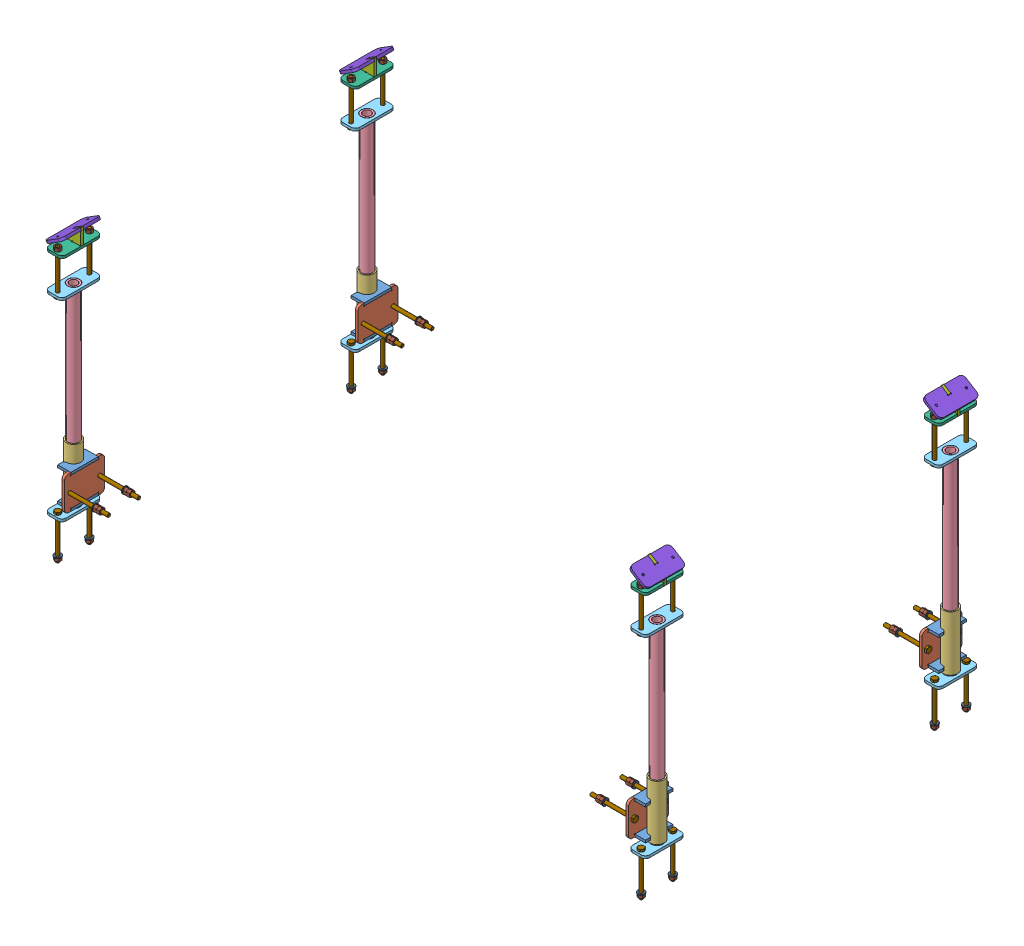
SolidWorks assembly Sliding mechanism^SPR-V1 0000.00-A Sheetpress assembly, configuration Default. Lengths in mm.
Overall size (1428.35 678.14 790).
108 component instances, 11 part files, 0 mates.
Components (placement in the parent):
- SPR-V1 1000.02-A Guide bracket-1: SPR-V1 1000.02-A Guide bracket [Default] at (665 -300 0) x (0 0 1) z (1 0 0) size (65 80 31)
- SPR-V1 1000.02-A Guide plate-1: SPR-V1 1000.02-A Guide plate [Default] at (665 -300 0) x (0 0 1) z (1 0 0) size (95 80 6)
- SPR-V1 1000.02-A Slider guide-1: SPR-V1 1000.02-A Slider guide [Default] at (665 -320 0) x (0 0 -1) z (0 1 0) size (34 34 130)
- SPR-V1 1000.03-A Slider rod-1: SPR-V1 1000.03-A Slider rod [Default] at (671 -420 0) x (0 0 -1) z (0 1 0) size (27 27 460)
- SPR-V1 1000.04-A Slider rod plate-1: SPR-V1 1000.04-A Slider rod plate [Default] at (671 -420 0) x (0 0 -1) z (0 1 0) size (95 40 6)
- SPR-V1 1000.05-A Hood bracket 1-1: SPR-V1 1000.05-A Hood bracket 1 [Default] at (0 120 0) x (1 0 0) z (0 1 0) size (40 95 6)
- SPR-V1 1000.05-A Hood bracket 2-1: SPR-V1 1000.05-A Hood bracket 2 [Default] at (0 0 -347.5) size (40 44.14 6)
- SPR-V1 1000.05-A Hood bracket 3-1: SPR-V1 1000.05-A Hood bracket 3 [Default] at (0 0 -347.5) size (44.82 31.06 95)
- SPR-V1 1000.02-A Slider guide-2: SPR-V1 1000.02-A Slider guide [Default] at (665 -370 0) x (0 0 1) z (0 -1 0) size (34 34 130)
- SPR-V1 1000.03-A Slider rod-2: SPR-V1 1000.03-A Slider rod [Default] at (671 40 0) x (0 0 1) z (0 -1 0) size (27 27 460)
- SPR-V1 1000.02-A Guide bracket-2: SPR-V1 1000.02-A Guide bracket [Default] at (665 -300 695) x (0 0 1) z (1 0 0) size (65 80 31)
- SPR-V1 1000.02-A Slider guide-3: SPR-V1 1000.02-A Slider guide [Default] at (-665 -370 0) x (0 0 -1) z (0 -1 0) size (34 34 130)
- SPR-V1 1000.03-A Slider rod-3: SPR-V1 1000.03-A Slider rod [Default] at (-671 40 0) x (0 0 -1) z (0 -1 0) size (27 27 460)
- SPR-V1 1000.02-A Guide bracket-3: SPR-V1 1000.02-A Guide bracket [Default] at (-665 -300 -695) x (0 0 -1) z (-1 0 0) size (65 80 31)
- SPR-V1 1000.02-A Slider guide-4: SPR-V1 1000.02-A Slider guide [Default] at (-665 -320 0) x (0 0 1) z (0 1 0) size (34 34 130)
- SPR-V1 1000.03-A Slider rod-4: SPR-V1 1000.03-A Slider rod [Default] at (-671 -420 0) x (0 0 1) z (0 1 0) size (27 27 460)
- SPR-V1 1000.02-A Guide bracket-4: SPR-V1 1000.02-A Guide bracket [Default] at (-665 -300 0) x (0 0 -1) z (-1 0 0) size (65 80 31)
- SPR-V1 1000.02-A Guide plate-2: SPR-V1 1000.02-A Guide plate [Default] at (671 -300 0) x (0 0 -1) z (-1 0 0) size (95 80 6)
- SPR-V1 1000.02-A Guide plate-3: SPR-V1 1000.02-A Guide plate [Default] at (-665 -300 0) x (0 0 -1) z (-1 0 0) size (95 80 6)
- SPR-V1 1000.02-A Guide plate-4: SPR-V1 1000.02-A Guide plate [Default] at (-671 -300 0) x (0 0 1) z (1 0 0) size (95 80 6)
- SPR-V1 1000.04-A Slider rod plate-2: SPR-V1 1000.04-A Slider rod plate [Default] at (671 -414 0) x (0 0 1) z (0 -1 0) size (95 40 6)
- SPR-V1 1000.04-A Slider rod plate-3: SPR-V1 1000.04-A Slider rod plate [Default] at (-671 -414 0) x (0 0 -1) z (0 -1 0) size (95 40 6)
- SPR-V1 1000.04-A Slider rod plate-4: SPR-V1 1000.04-A Slider rod plate [Default] at (-671 -420 0) x (0 0 1) z (0 1 0) size (95 40 6)
- SPR-V1 1000.04-A Slider rod plate-5: SPR-V1 1000.04-A Slider rod plate [Default] at (671 40 0) x (0 0 1) z (0 -1 0) size (95 40 6)
- SPR-V1 1000.04-A Slider rod plate-6: SPR-V1 1000.04-A Slider rod plate [Default] at (671 34 0) x (0 0 -1) z (0 1 0) size (95 40 6)
- SPR-V1 1000.04-A Slider rod plate-7: SPR-V1 1000.04-A Slider rod plate [Default] at (-671 40 0) x (0 0 -1) z (0 -1 0) size (95 40 6)
- SPR-V1 1000.04-A Slider rod plate-8: SPR-V1 1000.04-A Slider rod plate [Default] at (-671 34 0) x (0 0 1) z (0 1 0) size (95 40 6)
- SPR-V1 1000.05-A Hood bracket 1-2: SPR-V1 1000.05-A Hood bracket 1 [Default] at (0 126 0) x (-1 0 0) z (0 -1 0) size (40 95 6)
- SPR-V1 1000.05-A Hood bracket 2-2: SPR-V1 1000.05-A Hood bracket 2 [Default] at (0 0 -347.5) x (-1 0 0) z (0 0 -1) size (40 44.14 6)
- SPR-V1 1000.05-A Hood bracket 3-2: SPR-V1 1000.05-A Hood bracket 3 [Default] at (0 0 -347.5) x (-1 0 0) z (0 0 -1) size (44.82 31.06 95)
- SPR-V1 1000.05-A Hood bracket 1-3: SPR-V1 1000.05-A Hood bracket 1 [Default] at (0 126 0) x (1 0 0) z (0 -1 0) size (40 95 6)
- SPR-V1 1000.05-A Hood bracket 2-3: SPR-V1 1000.05-A Hood bracket 2 [Default] at (0 0 347.5) size (40 44.14 6)
- SPR-V1 1000.05-A Hood bracket 1-4: SPR-V1 1000.05-A Hood bracket 1 [Default] at (0 120 0) x (-1 0 0) z (0 1 0) size (40 95 6)
- SPR-V1 1000.05-A Hood bracket 2-4: SPR-V1 1000.05-A Hood bracket 2 [Default] at (0 0 347.5) x (-1 0 0) z (0 0 -1) size (40 44.14 6)
- SPR-V1 1000.05-A Hood bracket 3-3: SPR-V1 1000.05-A Hood bracket 3 [Default] at (0 0 347.5) x (-1 0 0) z (0 0 -1) size (44.82 31.06 95)
- SPR-V1 1000.05-A Hood bracket 3-4: SPR-V1 1000.05-A Hood bracket 3 [Default] at (0 0 347.5) size (44.82 31.06 95)
- hex bolt gradeab_iso_ISO 4014 - M8 x 100 x 100-N-1: hex bolt gradeab_iso_ISO 4014 - M8 x 100 x 100-N [Default] at (691 28.7 -385) x (0 1 0) z (0 0 1) size (105.3 15.01 13)
- hex bolt gradeab_iso_ISO 4014 - M8 x 100 x 100-N-2: hex bolt gradeab_iso_ISO 4014 - M8 x 100 x 100-N [Default] at (691 28.7 -310) x (0 1 0) z (0 0 1) size (105.3 15.01 13)
- hex bolt gradeab_iso_ISO 4014 - M8 x 100 x 100-N-3: hex bolt gradeab_iso_ISO 4014 - M8 x 100 x 100-N [Default] at (691 28.7 385) x (0 1 0) z (0 0 1) size (105.3 15.01 13)
- hex bolt gradeab_iso_ISO 4014 - M8 x 100 x 100-N-4: hex bolt gradeab_iso_ISO 4014 - M8 x 100 x 100-N [Default] at (691 28.7 310) x (0 1 0) z (0 0 1) size (105.3 15.01 13)
- hex bolt gradeab_iso_ISO 4014 - M8 x 100 x 100-N-5: hex bolt gradeab_iso_ISO 4014 - M8 x 100 x 100-N [Default] at (691 -408.7 -385) x (0 -1 0) z (0 0 1) size (105.3 15.01 13)
- hex bolt gradeab_iso_ISO 4014 - M8 x 100 x 100-N-6: hex bolt gradeab_iso_ISO 4014 - M8 x 100 x 100-N [Default] at (691 -408.7 310) x (0 -1 0) z (0 0 1) size (105.3 15.01 13)
- hex bolt gradeab_iso_ISO 4014 - M8 x 100 x 100-N-7: hex bolt gradeab_iso_ISO 4014 - M8 x 100 x 100-N [Default] at (691 -408.7 385) x (0 -1 0) z (0 0 1) size (105.3 15.01 13)
- hex bolt gradeab_iso_ISO 4014 - M8 x 100 x 100-N-8: hex bolt gradeab_iso_ISO 4014 - M8 x 100 x 100-N [Default] at (691 -408.7 -310) x (0 -1 0) z (0 0 1) size (105.3 15.01 13)
- hex bolt gradeab_iso_ISO 4014 - M8 x 100 x 100-N-9: hex bolt gradeab_iso_ISO 4014 - M8 x 100 x 100-N [Default] at (676.3 -360 -383) x (-1 0 0) z (0 0.924225 0.381849) size (105.3 15.01 13)
- hex bolt gradeab_iso_ISO 4014 - M8 x 100 x 100-N-10: hex bolt gradeab_iso_ISO 4014 - M8 x 100 x 100-N [Default] at (676.3 -360 -312) x (-1 0 0) z (0 0.924225 0.381849) size (105.3 15.01 13)
- hex bolt gradeab_iso_ISO 4014 - M8 x 100 x 100-N-11: hex bolt gradeab_iso_ISO 4014 - M8 x 100 x 100-N [Default] at (676.3 -360 312) x (-1 0 0) z (0 0.924225 0.381849) size (105.3 15.01 13)
- hex bolt gradeab_iso_ISO 4014 - M8 x 100 x 100-N-12: hex bolt gradeab_iso_ISO 4014 - M8 x 100 x 100-N [Default] at (676.3 -360 383) x (-1 0 0) z (0 0.924225 0.381849) size (105.3 15.01 13)
- hex bolt gradeab_iso_ISO 4014 - M8 x 100 x 100-N-13: hex bolt gradeab_iso_ISO 4014 - M8 x 100 x 100-N [Default] at (-676.3 -360 -383) size (105.3 15.01 13)
- hex bolt gradeab_iso_ISO 4014 - M8 x 100 x 100-N-14: hex bolt gradeab_iso_ISO 4014 - M8 x 100 x 100-N [Default] at (-676.3 -360 -312) size (105.3 15.01 13)
- hex bolt gradeab_iso_ISO 4014 - M8 x 100 x 100-N-15: hex bolt gradeab_iso_ISO 4014 - M8 x 100 x 100-N [Default] at (-676.3 -360 312) size (105.3 15.01 13)
- hex bolt gradeab_iso_ISO 4014 - M8 x 100 x 100-N-16: hex bolt gradeab_iso_ISO 4014 - M8 x 100 x 100-N [Default] at (-676.3 -360 383) size (105.3 15.01 13)
- plain washer normal grade a_iso_Washer ISO 7089 - 8-1: plain washer normal grade a_iso_Washer ISO 7089 - 8 [Default] at (605 -360 -383) size (1.6 16 16)
- plain washer normal grade a_iso_Washer ISO 7089 - 8-2: plain washer normal grade a_iso_Washer ISO 7089 - 8 [Default] at (605 -360 -312) size (1.6 16 16)
- plain washer normal grade a_iso_Washer ISO 7089 - 8-3: plain washer normal grade a_iso_Washer ISO 7089 - 8 [Default] at (605 -360 312) size (1.6 16 16)
- plain washer normal grade a_iso_Washer ISO 7089 - 8-4: plain washer normal grade a_iso_Washer ISO 7089 - 8 [Default] at (605 -360 383) size (1.6 16 16)
- plain washer normal grade a_iso_Washer ISO 7089 - 8-5: plain washer normal grade a_iso_Washer ISO 7089 - 8 [Default] at (-605 -360 -383) x (-1 0 0) z (0 0.924225 0.381849) size (1.6 16 16)
- plain washer normal grade a_iso_Washer ISO 7089 - 8-6: plain washer normal grade a_iso_Washer ISO 7089 - 8 [Default] at (-605 -360 -312) x (-1 0 0) z (0 0.924225 0.381849) size (1.6 16 16)
- plain washer normal grade a_iso_Washer ISO 7089 - 8-7: plain washer normal grade a_iso_Washer ISO 7089 - 8 [Default] at (-605 -360 383) x (-1 0 0) z (0 0.924225 0.381849) size (1.6 16 16)
- plain washer normal grade a_iso_Washer ISO 7089 - 8-8: plain washer normal grade a_iso_Washer ISO 7089 - 8 [Default] at (-605 -360 312) x (-1 0 0) z (0 0.924225 0.381849) size (1.6 16 16)
- hex nut gradec_iso_ISO - 4034 - M8 - N-1: hex nut gradec_iso_ISO - 4034 - M8 - N [Default] at (595.5 -360 -383) x (0 0 1) z (-1 0 0) size (13 15.01 7.9)
- hex nut gradec_iso_ISO - 4034 - M8 - N-2: hex nut gradec_iso_ISO - 4034 - M8 - N [Default] at (587.6 -360 -383) x (0 0 1) z (-1 0 0) size (13 15.01 7.9)
- hex nut gradec_iso_ISO - 4034 - M8 - N-3: hex nut gradec_iso_ISO - 4034 - M8 - N [Default] at (595.5 -360 -312) x (0 0 1) z (-1 0 0) size (13 15.01 7.9)
- hex nut gradec_iso_ISO - 4034 - M8 - N-4: hex nut gradec_iso_ISO - 4034 - M8 - N [Default] at (587.6 -360 -312) x (0 0 1) z (-1 0 0) size (13 15.01 7.9)
- hex nut gradec_iso_ISO - 4034 - M8 - N-5: hex nut gradec_iso_ISO - 4034 - M8 - N [Default] at (595.5 -360 312) x (0 0 1) z (-1 0 0) size (13 15.01 7.9)
- hex nut gradec_iso_ISO - 4034 - M8 - N-6: hex nut gradec_iso_ISO - 4034 - M8 - N [Default] at (595.5 -360 383) x (0 0 1) z (-1 0 0) size (13 15.01 7.9)
- hex nut gradec_iso_ISO - 4034 - M8 - N-7: hex nut gradec_iso_ISO - 4034 - M8 - N [Default] at (587.6 -360 312) x (0 0 1) z (-1 0 0) size (13 15.01 7.9)
- hex nut gradec_iso_ISO - 4034 - M8 - N-8: hex nut gradec_iso_ISO - 4034 - M8 - N [Default] at (587.6 -360 383) x (0 0 1) z (-1 0 0) size (13 15.01 7.9)
- hex nut gradec_iso_ISO - 4034 - M8 - N-9: hex nut gradec_iso_ISO - 4034 - M8 - N [Default] at (-595.5 -360 -312) x (0 0 -1) z (1 0 0) size (13 15.01 7.9)
- hex nut gradec_iso_ISO - 4034 - M8 - N-10: hex nut gradec_iso_ISO - 4034 - M8 - N [Default] at (-595.5 -360 -383) x (0 0 -1) z (1 0 0) size (13 15.01 7.9)
- hex nut gradec_iso_ISO - 4034 - M8 - N-11: hex nut gradec_iso_ISO - 4034 - M8 - N [Default] at (-587.6 -360 -312) x (0 0 -1) z (1 0 0) size (13 15.01 7.9)
- hex nut gradec_iso_ISO - 4034 - M8 - N-12: hex nut gradec_iso_ISO - 4034 - M8 - N [Default] at (-587.6 -360 -383) x (0 0 -1) z (1 0 0) size (13 15.01 7.9)
- hex nut gradec_iso_ISO - 4034 - M8 - N-13: hex nut gradec_iso_ISO - 4034 - M8 - N [Default] at (-595.5 -360 383) x (0 0 -1) z (1 0 0) size (13 15.01 7.9)
- hex nut gradec_iso_ISO - 4034 - M8 - N-14: hex nut gradec_iso_ISO - 4034 - M8 - N [Default] at (-595.5 -360 312) x (0 0 -1) z (1 0 0) size (13 15.01 7.9)
- hex nut gradec_iso_ISO - 4034 - M8 - N-15: hex nut gradec_iso_ISO - 4034 - M8 - N [Default] at (-587.6 -360 383) x (0 0 -1) z (1 0 0) size (13 15.01 7.9)
- hex nut gradec_iso_ISO - 4034 - M8 - N-16: hex nut gradec_iso_ISO - 4034 - M8 - N [Default] at (-587.6 -360 312) x (0 0 -1) z (1 0 0) size (13 15.01 7.9)
- hex bolt gradeab_iso_ISO 4014 - M8 x 100 x 100-N-17: hex bolt gradeab_iso_ISO 4014 - M8 x 100 x 100-N [Default] at (-691 -408.7 310) x (0 -1 0) z (0 0 1) size (105.3 15.01 13)
- hex bolt gradeab_iso_ISO 4014 - M8 x 100 x 100-N-18: hex bolt gradeab_iso_ISO 4014 - M8 x 100 x 100-N [Default] at (-691 -408.7 -310) x (0 -1 0) z (0 0 1) size (105.3 15.01 13)
- hex bolt gradeab_iso_ISO 4014 - M8 x 100 x 100-N-19: hex bolt gradeab_iso_ISO 4014 - M8 x 100 x 100-N [Default] at (-691 -408.7 385) x (0 -1 0) z (0 0 1) size (105.3 15.01 13)
- hex bolt gradeab_iso_ISO 4014 - M8 x 100 x 100-N-20: hex bolt gradeab_iso_ISO 4014 - M8 x 100 x 100-N [Default] at (-691 -408.7 -385) x (0 -1 0) z (0 0 1) size (105.3 15.01 13)
- plain washer normal grade a_iso_Washer ISO 7089 - 8-9: plain washer normal grade a_iso_Washer ISO 7089 - 8 [Default] at (691 -500 -385) x (0 1 0) z (0 0 1) size (1.6 16 16)
- plain washer normal grade a_iso_Washer ISO 7089 - 8-10: plain washer normal grade a_iso_Washer ISO 7089 - 8 [Default] at (691 -500 -310) x (0 1 0) z (0 0 1) size (1.6 16 16)
- plain washer normal grade a_iso_Washer ISO 7089 - 8-11: plain washer normal grade a_iso_Washer ISO 7089 - 8 [Default] at (691 -500 310) x (0 1 0) z (0 0 1) size (1.6 16 16)
- plain washer normal grade a_iso_Washer ISO 7089 - 8-12: plain washer normal grade a_iso_Washer ISO 7089 - 8 [Default] at (691 -500 385) x (0 1 0) z (0 0 1) size (1.6 16 16)
- plain washer normal grade a_iso_Washer ISO 7089 - 8-13: plain washer normal grade a_iso_Washer ISO 7089 - 8 [Default] at (-691 -500 -385) x (0 1 0) z (0 0 1) size (1.6 16 16)
- plain washer normal grade a_iso_Washer ISO 7089 - 8-14: plain washer normal grade a_iso_Washer ISO 7089 - 8 [Default] at (-691 -500 -310) x (0 1 0) z (0 0 1) size (1.6 16 16)
- plain washer normal grade a_iso_Washer ISO 7089 - 8-15: plain washer normal grade a_iso_Washer ISO 7089 - 8 [Default] at (-691 -500 385) x (0 1 0) z (0 0 1) size (1.6 16 16)
- plain washer normal grade a_iso_Washer ISO 7089 - 8-16: plain washer normal grade a_iso_Washer ISO 7089 - 8 [Default] at (-691 -500 310) x (0 1 0) z (0 0 1) size (1.6 16 16)
- hex nut gradec_iso_ISO - 4034 - M8 - N-17: hex nut gradec_iso_ISO - 4034 - M8 - N [Default] at (691 -509.5 -385) x (1 0 0) z (0 -1 0) size (13 15.01 7.9)
- hex nut gradec_iso_ISO - 4034 - M8 - N-18: hex nut gradec_iso_ISO - 4034 - M8 - N [Default] at (691 -509.5 -310) x (1 0 0) z (0 -1 0) size (13 15.01 7.9)
- hex nut gradec_iso_ISO - 4034 - M8 - N-19: hex nut gradec_iso_ISO - 4034 - M8 - N [Default] at (691 -509.5 310) x (1 0 0) z (0 -1 0) size (13 15.01 7.9)
- hex nut gradec_iso_ISO - 4034 - M8 - N-20: hex nut gradec_iso_ISO - 4034 - M8 - N [Default] at (691 -509.5 385) x (1 0 0) z (0 -1 0) size (13 15.01 7.9)
- hex nut gradec_iso_ISO - 4034 - M8 - N-21: hex nut gradec_iso_ISO - 4034 - M8 - N [Default] at (-691 -509.5 -310) x (1 0 0) z (0 -1 0) size (13 15.01 7.9)
- hex nut gradec_iso_ISO - 4034 - M8 - N-22: hex nut gradec_iso_ISO - 4034 - M8 - N [Default] at (-691 -509.5 -385) x (1 0 0) z (0 -1 0) size (13 15.01 7.9)
- hex nut gradec_iso_ISO - 4034 - M8 - N-23: hex nut gradec_iso_ISO - 4034 - M8 - N [Default] at (-691 -509.5 385) x (1 0 0) z (0 -1 0) size (13 15.01 7.9)
- hex nut gradec_iso_ISO - 4034 - M8 - N-24: hex nut gradec_iso_ISO - 4034 - M8 - N [Default] at (-691 -509.5 310) x (1 0 0) z (0 -1 0) size (13 15.01 7.9)
- hex bolt gradeab_iso_ISO 4014 - M8 x 100 x 100-N-21: hex bolt gradeab_iso_ISO 4014 - M8 x 100 x 100-N [Default] at (-691 28.7 385) x (0 1 0) z (0 0 1) size (105.3 15.01 13)
- hex nut gradec_iso_ISO - 4034 - M8 - N-25: hex nut gradec_iso_ISO - 4034 - M8 - N [Default] at (691 133.9 385) x (1 0 0) z (0 1 0) size (13 15.01 7.9)
- hex nut gradec_iso_ISO - 4034 - M8 - N-26: hex nut gradec_iso_ISO - 4034 - M8 - N [Default] at (691 133.9 -310) x (1 0 0) z (0 1 0) size (13 15.01 7.9)
- hex nut gradec_iso_ISO - 4034 - M8 - N-27: hex nut gradec_iso_ISO - 4034 - M8 - N [Default] at (691 133.9 310) x (1 0 0) z (0 1 0) size (13 15.01 7.9)
- hex nut gradec_iso_ISO - 4034 - M8 - N-28: hex nut gradec_iso_ISO - 4034 - M8 - N [Default] at (691 133.9 -385) x (1 0 0) z (0 1 0) size (13 15.01 7.9)
- hex bolt gradeab_iso_ISO 4014 - M8 x 100 x 100-N-22: hex bolt gradeab_iso_ISO 4014 - M8 x 100 x 100-N [Default] at (-691 28.7 -385) x (0 1 0) z (0 0 1) size (105.3 15.01 13)
- hex bolt gradeab_iso_ISO 4014 - M8 x 100 x 100-N-23: hex bolt gradeab_iso_ISO 4014 - M8 x 100 x 100-N [Default] at (-691 28.7 310) x (0 1 0) z (0 0 1) size (105.3 15.01 13)
- hex bolt gradeab_iso_ISO 4014 - M8 x 100 x 100-N-24: hex bolt gradeab_iso_ISO 4014 - M8 x 100 x 100-N [Default] at (-691 28.7 -310) x (0 1 0) z (0.297271 0 0.954793) size (105.3 15.01 13)
- hex nut gradec_iso_ISO - 4034 - M8 - N-29: hex nut gradec_iso_ISO - 4034 - M8 - N [Default] at (-691 133.9 -310) x (1 0 0) z (0 1 0) size (13 15.01 7.9)
- hex nut gradec_iso_ISO - 4034 - M8 - N-30: hex nut gradec_iso_ISO - 4034 - M8 - N [Default] at (-691 133.9 -385) x (1 0 0) z (0 1 0) size (13 15.01 7.9)
- hex nut gradec_iso_ISO - 4034 - M8 - N-31: hex nut gradec_iso_ISO - 4034 - M8 - N [Default] at (-691 133.9 385) x (1 0 0) z (0 1 0) size (13 15.01 7.9)
- hex nut gradec_iso_ISO - 4034 - M8 - N-32: hex nut gradec_iso_ISO - 4034 - M8 - N [Default] at (-691 133.9 310) x (1 0 0) z (0 1 0) size (13 15.01 7.9)
